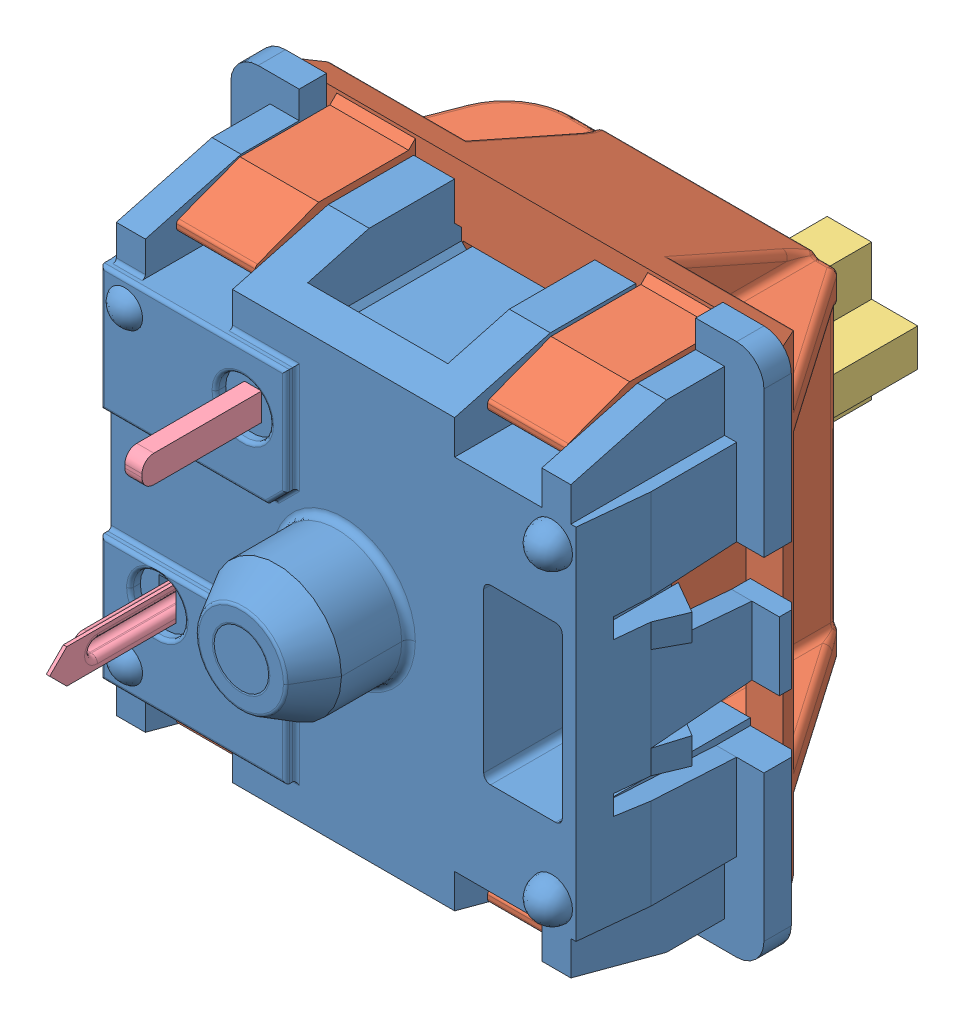
SolidWorks assembly Cherry MX Switch Plate Mounted, configuration Default. Lengths in mm.
Overall size (15.6 15.6 18.6).
7 component instances, 6 part files, 0 mates.
Components (placement in the parent):
- asm_mx_asm_PLATE.stp-1: asm_mx_asm_PLATE.stp [Default] at origin size (15.6 15.6 18.6)
  - MX_DOWN.stp-1: MX_DOWN.stp [Default] at (0.3071 0.3071 -0.3425) size (15.6 15.6 12.1)
  - MX_UP.stp-1: MX_UP.stp [Default] at (0.3071 0.3071 -5.7425) size (14.71 14.71 9.89)
  - UP_MX.stp-1: UP_MX.stp [Default] at (3.1571 0.3071 0.4575) x (0 1 0) z (-1 0 0) size (8.9 12.4 5.7)
  - MX_PIN.stp-1: MX_PIN.stp [Default] at (-2.5929 4.0071 8.4575) x (0 -1 0) z (1 0 0) size (9.8 13.12 3.74)
  - MX_SPRING.stp-1: MX_SPRING.stp [Default] at (0.3071 0.3071 6.7575) size (3.27 3.27 11.31)
  - MX_CLICK.stp-1: MX_CLICK.stp [Default] at (-2.1462 -4.1429 2.1523) x (1 0 0) z (0 1 0) size (6.85 3.85 8.9)
